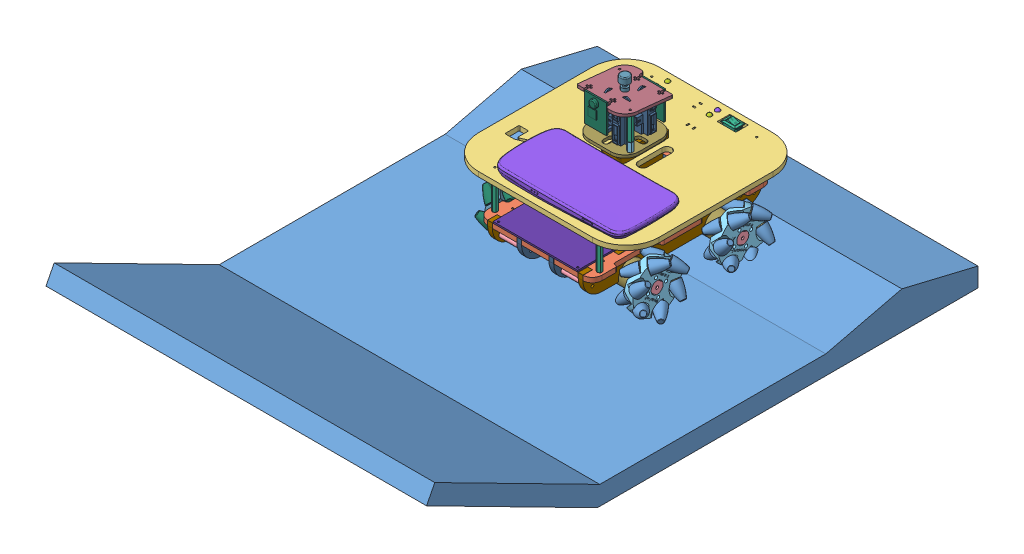
SolidWorks assembly Robo_02, configuration Valor predeterminado. Lengths in mm.
Overall size (190 176.15 190).
196 component instances, 38 part files, 87 mates.
Components (placement in the parent):
- Rampa-1: Rampa [Valor predeterminado] at (-210.2935 -119.2704 146.4332) x (0 0 -1) z (1 0 0) size (579.56 108.37 400) (hidden)
- Plataforma_1-1: Plataforma_1 [Valor predeterminado] at (-69.9818 -54.6704 16.9892) size (120 5 190)
- Plataforma_2-1: Plataforma_2 [Valor predeterminado] at (-109.9818 -15.1704 16.9892) size (190 5 190)
- PC-Standoff - 25mm - FF-1: PC-Standoff - 25mm - FF [Valor predeterminado] at (35.0182 -64.6704 1.9892) x (0 0.998329 -0.057794) z (0 0.057794 0.998329) size (6.5 25 6.5)
- PC-Standoff - 25mm - FF-2: PC-Standoff - 25mm - FF [Valor predeterminado] at (-55.1818 -64.6704 1.9892) x (0 -0.434626 0.900611) z (0 0.900611 0.434626) size (6.5 25 6.5)
- PC-Standoff - 25mm - FF-3: PC-Standoff - 25mm - FF [Valor predeterminado] at (-55.1818 -64.6704 -168.0108) x (0 -0.434626 0.900611) z (0 0.900611 0.434626) size (6.5 25 6.5)
- PC-Standoff - 25mm - FF-4: PC-Standoff - 25mm - FF [Valor predeterminado] at (35.0182 -64.6704 -168.0108) x (0 0.998329 -0.057794) z (0 0.057794 0.998329) size (6.5 25 6.5)
- PC-Standoff - 9.5mm - FF-1: PC-Standoff - 9.5mm - FF [Valor predeterminado] at (-64.9818 -24.6704 -0.5108) x (0.618827 0 0.785527) z (-0.785527 0 0.618827) size (5.5 9.5 4.76)
- PC-Standoff - 9.5mm - FF-2: PC-Standoff - 9.5mm - FF [Valor predeterminado] at (45.0182 -24.6704 -0.5108) x (0 0 1) z (-1 0 0) size (5.5 9.5 4.76)
- PC-Standoff - 9.5mm - FF-3: PC-Standoff - 9.5mm - FF [Valor predeterminado] at (-64.9818 -24.6704 -165.5108) x (0 0 1) z (-1 0 0) size (5.5 9.5 4.76)
- PC-Standoff - 9.5mm - FF-4: PC-Standoff - 9.5mm - FF [Valor predeterminado] at (45.0182 -24.6704 -165.5108) x (0.176181 0 0.984358) z (-0.984358 0 0.176181) size (5.5 9.5 4.76)
- PC-Standoff - 25mm-6: PC-Standoff - 25mm [Valor predeterminado] at (45.0182 -24.6704 -165.5108) x (-0.176181 0 -0.984358) z (-0.984358 0 0.176181) size (5.5 29.76 4.76)
- PC-Standoff - 25mm-7: PC-Standoff - 25mm [Valor predeterminado] at (45.0182 -24.6704 -0.5108) x (0 0 -1) z (-1 0 0) size (5.5 29.76 4.76)
- PC-Standoff - 25mm-8: PC-Standoff - 25mm [Valor predeterminado] at (-64.9818 -24.6704 -0.5108) x (0 0 -1) z (-1 0 0) size (5.5 29.76 4.76)
- PC-Standoff - 25mm-1: PC-Standoff - 25mm [Valor predeterminado] at (-64.9818 -24.6704 -165.5108) x (0 0 -1) z (-1 0 0) size (5.5 29.76 4.76)
- bateriaLiPO-2: bateriaLiPO [Valor predeterminado] at (-61.3132 -20.1704 -106.4354) x (0 0 1) z (0 -1 0) size (105 34 24)
- Nexus-1: Nexus [Default] at (-25.3253 -39.7124 4.2312) x (0.005944 0 0.999982) z (0 1 0) size (78.79 147.01 23.11)
- viga_motor_1-1: viga_motor_1 [Valor predeterminado] at (35.0182 -74.6704 11.9892) x (0 0 -1) z (1 0 0) size (190 25 5)
- viga_motor_2-1: viga_motor_2 [Valor predeterminado] at (4.3182 -74.6704 11.9892) x (0 0 -1) z (1 0 0) size (190 25 5)
- viga_motor_2-3: viga_motor_2 [Valor predeterminado] at (-29.4818 -74.6704 11.9892) x (0 0 -1) z (1 0 0) size (190 25 5)
- viga_motor_1-2: viga_motor_1 [Valor predeterminado] at (-60.1818 -74.6704 11.9892) x (0 0 -1) z (1 0 0) size (190 25 5)
- Motor-7: Motor [Valor predeterminado] at (-22.1818 -72.6522 -31.5439) x (0 -0.006022 0.999982) z (-1 0 0) size (25 25 76.2)
  - Motor-1: Motor [Valor predeterminado] at (-6.4714 0.7429 0) size (24.4 24.4 45.8)
  - Motor_Redutor-1: Motor_Redutor [Valor predeterminado] at (-6.4714 0.7429 30.8) size (25 25 33.5)
  - Encoder-1: Encoder [Valor predeterminado] at (-6.4714 0.7429 -2) x (1 0 0) z (0 1 0) size (23 9.9 23)
- Motor-8: Motor [Valor predeterminado] at (-22.1818 -70.3376 -134.3418) x (0 0.122928 -0.992416) z (-1 0 0) size (25 25 76.2)
  - Motor-1: Motor [Valor predeterminado] at (-6.4714 0.7429 0) size (24.4 24.4 45.8)
  - Motor_Redutor-1: Motor_Redutor [Valor predeterminado] at (-6.4714 0.7429 30.8) size (25 25 33.5)
  - Encoder-1: Encoder [Valor predeterminado] at (-6.4714 0.7429 -2) x (1 0 0) z (0 1 0) size (23 9.9 23)
- Motor-1: Motor [Valor predeterminado] at (2.2182 -71.179 -121.5336) x (0 -0.007948 0.999968) z (1 0 0) size (25 25 76.2)
  - Motor-1: Motor [Valor predeterminado] at (-6.4714 0.7429 0) size (24.4 24.4 45.8)
  - Motor_Redutor-1: Motor_Redutor [Valor predeterminado] at (-6.4714 0.7429 30.8) size (25 25 33.5)
  - Encoder-1: Encoder [Valor predeterminado] at (-6.4714 0.7429 -2) x (1 0 0) z (0 1 0) size (23 9.9 23)
- Motor-2: Motor [Valor predeterminado] at (2.2182 -73.8625 -31.8089) x (0 -0.412409 0.910999) z (1 0 0) size (25 25 76.2)
  - Motor-1: Motor [Valor predeterminado] at (-6.4714 0.7429 0) size (24.4 24.4 45.8)
  - Motor_Redutor-1: Motor_Redutor [Valor predeterminado] at (-6.4714 0.7429 30.8) size (25 25 33.5)
  - Encoder-1: Encoder [Valor predeterminado] at (-6.4714 0.7429 -2) x (1 0 0) z (0 1 0) size (23 9.9 23)
- Mecanum Wheel B-3: Mecanum Wheel B [Valor predeterminado] at (-98.1018 -64.626 -40.1882) x (-1 0 0) z (0 -0.940085 0.340939) size (40.55 59.83 66.05)
  - Mecanum Hub Mirrored B R2-1: Mecanum Hub Mirrored B R2 [Valor predeterminado] at (-14.8574 0.4229 7.5528) size (9.53 50.8 50.8)
  - rubber roller_1-1: rubber roller_1 [Valor predeterminado] at (-17.3237 21.0604 5.0865) x (-0.707107 0 -0.707107) z (0.499904 -0.707242 -0.499904) size (15.88 13.22 13.13)
  - rubber roller_1-2: rubber roller_1 [Valor predeterminado] at (-17.3231 12.877 24.1925) x (-0.707107 0.612372 -0.353553) z (0.253872 -0.246803 -0.93522) size (15.88 13.22 13.13)
  - rubber roller_1-3: rubber roller_1 [Valor predeterminado] at (-17.3231 -7.7605 26.6582) x (-0.707107 0.612372 0.353553) z (-0.391226 -0.75531 0.525784) size (15.88 13.22 13.13)
  - rubber roller_1-4: rubber roller_1 [Valor predeterminado] at (-17.3231 -20.2146 10.0185) x (-0.707107 0 0.707107) z (0.562502 0.605957 0.562502) size (15.88 13.22 13.13)
  - rubber roller_1-5: rubber roller_1 [Valor predeterminado] at (-17.3231 8.6063 -11.5527) x (-0.707107 -0.612372 -0.353553) z (-0.707107 0.61243 0.353453) size (15.88 13.22 13.13)
  - rubber roller_1-6: rubber roller_1 [Valor predeterminado] at (-17.3231 -12.0312 -9.087) x (-0.707107 -0.612372 0.353553) z (-0.5772 0.788695 0.211661) size (15.88 13.22 13.13)
  - rubber roller_1-7: rubber roller_1 [Valor predeterminado] at (-12.3912 -12.0317 24.1922) x (0.707107 -0.612372 -0.353553) z (-0.685872 -0.715596 -0.132296) size (15.88 13.22 13.13)
  - rubber roller_1-8: rubber roller_1 [Valor predeterminado] at (-12.3912 -20.2146 5.0865) x (0.707107 0 -0.707107) z (-0.253824 0.933352 -0.253824) size (15.88 13.22 13.13)
  - rubber roller_1-9: rubber roller_1 [Valor predeterminado] at (-12.3912 -7.76 -11.553) x (0.707107 0.612372 -0.353553) z (-0.001796 -0.498443 -0.866921) size (15.88 13.22 13.13)
  - rubber roller_1-10: rubber roller_1 [Valor predeterminado] at (-12.3912 8.6058 26.6585) x (0.707107 -0.612372 0.353553) z (0.069934 0.558113 0.826813) size (15.88 13.22 13.13)
  - rubber roller_1-11: rubber roller_1 [Valor predeterminado] at (-12.3912 12.8775 -9.0867) x (0.707107 0.612372 0.353553) z (-0.460574 0.01948 0.887408) size (15.88 13.22 13.13)
  - rubber roller_1-12: rubber roller_1 [Valor predeterminado] at (-12.3912 21.0604 10.019) x (0.707107 0 0.707107) z (-0.138038 -0.98076 0.138038) size (15.88 13.22 13.13)
  - steel pin_1-1: steel pin_1 [Valor predeterminado] at (-5.6406 21.0604 16.7696) x (-0.707107 0 -0.707107) z (-0.548656 0.630836 0.548656) size (32.38 3.18 3.18)
  - steel pin_1-2: steel pin_1 [Valor predeterminado] at (-3.4109 0.8287 31.1486) x (-0.707107 0.612372 -0.353553) z (-0.30884 -0.717251 -0.624635) size (32.38 3.18 3.18)
  - steel pin_1-3: steel pin_1 [Valor predeterminado] at (-3.4109 -19.8088 19.7021) x (-0.707107 0.612372 0.353553) z (0.672023 0.737529 0.066609) size (32.38 3.18 3.18)
  - steel pin_1-4: steel pin_1 [Valor predeterminado] at (-3.4109 -20.2146 -3.8938) x (-0.707107 0 0.707107) z (-0.643237 0.415323 -0.643237) size (32.38 3.18 3.18)
  - steel pin_1-5: steel pin_1 [Valor predeterminado] at (-3.4109 0.0171 -16.0431) x (-0.707107 -0.612372 0.353553) z (0.683232 -0.462866 0.564756) size (32.38 3.18 3.18)
  - steel pin_1-6: steel pin_1 [Valor predeterminado] at (-3.4109 20.6546 -4.5966) x (-0.707107 -0.612372 -0.353553) z (-0.635525 0.769593 -0.061923) size (32.38 3.18 3.18)
  - Flat Washer Type A Narrow_AI_FW 0.125_1-1: Flat Washer Type A Narrow_AI_FW 0.125_1 [Valor predeterminado] at (-12.9659 21.0604 9.4443) x (-0.707107 0 -0.707107) z (0.699565 0.145662 -0.699565) size (0.81 7.92 7.92)
  - Flat Washer Type A Narrow_AI_FW 0.125_1-2: Flat Washer Type A Narrow_AI_FW 0.125_1 [Valor predeterminado] at (-12.9659 12.3797 -9.3741) x (-0.707107 -0.612372 -0.353553) z (0.353553 -0.739199 0.573223) size (0.81 7.92 7.92)
  - Flat Washer Type A Narrow_AI_FW 0.125_1-3: Flat Washer Type A Narrow_AI_FW 0.125_1 [Valor predeterminado] at (-12.9659 -8.2578 -11.2656) x (-0.707107 -0.612372 0.353553) z (-0.353553 0.739199 0.573223) size (0.81 7.92 7.92)
  - Flat Washer Type A Narrow_AI_FW 0.125_1-4: Flat Washer Type A Narrow_AI_FW 0.125_1 [Valor predeterminado] at (-12.9659 -20.2146 5.6612) x (-0.707107 0 0.707107) z (-0.707107 0 -0.707107) size (0.81 7.92 7.92)
  - Flat Washer Type A Narrow_AI_FW 0.125_1-5: Flat Washer Type A Narrow_AI_FW 0.125_1 [Valor predeterminado] at (-12.9659 -11.5339 24.4796) x (-0.707107 0.612372 0.353553) z (-0.353553 -0.739199 0.573223) size (0.81 7.92 7.92)
  - Flat Washer Type A Narrow_AI_FW 0.125_1-6: Flat Washer Type A Narrow_AI_FW 0.125_1 [Valor predeterminado] at (-12.9659 9.1036 26.3711) x (-0.707107 0.612372 -0.353553) z (0.353553 0.739199 0.573223) size (0.81 7.92 7.92)
  - Flat Washer Type A Narrow_AI_FW 0.125_1-7: Flat Washer Type A Narrow_AI_FW 0.125_1 [Valor predeterminado] at (-16.7489 9.1036 -11.2656) x (0.707107 0.612372 0.353553) z (-0.353553 -0.126826 0.926777) size (0.81 7.92 7.92)
  - Flat Washer Type A Narrow_AI_FW 0.125_1-8: Flat Washer Type A Narrow_AI_FW 0.125_1 [Valor predeterminado] at (-16.7489 21.0604 5.6612) x (0.707107 0 0.707107) z (-0.707107 0 0.707107) size (0.81 7.92 7.92)
  - Flat Washer Type A Narrow_AI_FW 0.125_1-9: Flat Washer Type A Narrow_AI_FW 0.125_1 [Valor predeterminado] at (-16.7489 12.3797 24.4796) x (0.707107 -0.612372 0.353553) z (-0.353553 0.126826 0.926777) size (0.81 7.92 7.92)
  - Flat Washer Type A Narrow_AI_FW 0.125_1-10: Flat Washer Type A Narrow_AI_FW 0.125_1 [Valor predeterminado] at (-16.7489 -11.5339 -9.3741) x (0.707107 0.612372 -0.353553) z (0.353553 0.126826 0.926777) size (0.81 7.92 7.92)
  - Flat Washer Type A Narrow_AI_FW 0.125_1-11: Flat Washer Type A Narrow_AI_FW 0.125_1 [Valor predeterminado] at (-16.7489 -20.2146 9.4443) x (0.707107 0 -0.707107) z (0.707107 0 0.707107) size (0.81 7.92 7.92)
  - Flat Washer Type A Narrow_AI_FW 0.125_1-12: Flat Washer Type A Narrow_AI_FW 0.125_1 [Valor predeterminado] at (-16.7489 -8.2578 26.3711) x (0.707107 -0.612372 -0.353553) z (0.353553 -0.126826 0.926777) size (0.81 7.92 7.92)
  - Mecanum mount R2_1-1: Mecanum mount R2_1 [Valor predeterminado] at (-16.4449 0.4229 7.5528) x (-1 0 0) z (0 0 -1) size (9.53 25.4 25.4)
- Mecanum Wheel B-4: Mecanum Wheel B [Valor predeterminado] at (-98.1018 -76.851 -122.3172) x (-1 0 0) z (0 0.615302 -0.788291) size (40.55 59.83 66.05)
  - Mecanum Hub Mirrored B R2-1: Mecanum Hub Mirrored B R2 [Valor predeterminado] at (-14.8574 0.4229 7.5528) size (9.53 50.8 50.8)
  - rubber roller_1-1: rubber roller_1 [Valor predeterminado] at (-17.3237 21.0604 5.0865) x (-0.707107 0 -0.707107) z (0.499904 -0.707242 -0.499904) size (15.88 13.22 13.13)
  - rubber roller_1-2: rubber roller_1 [Valor predeterminado] at (-17.3231 12.877 24.1925) x (-0.707107 0.612372 -0.353553) z (0.253872 -0.246803 -0.93522) size (15.88 13.22 13.13)
  - rubber roller_1-3: rubber roller_1 [Valor predeterminado] at (-17.3231 -7.7605 26.6582) x (-0.707107 0.612372 0.353553) z (-0.391226 -0.75531 0.525784) size (15.88 13.22 13.13)
  - rubber roller_1-4: rubber roller_1 [Valor predeterminado] at (-17.3231 -20.2146 10.0185) x (-0.707107 0 0.707107) z (0.562502 0.605957 0.562502) size (15.88 13.22 13.13)
  - rubber roller_1-5: rubber roller_1 [Valor predeterminado] at (-17.3231 8.6063 -11.5527) x (-0.707107 -0.612372 -0.353553) z (-0.707107 0.61243 0.353453) size (15.88 13.22 13.13)
  - rubber roller_1-6: rubber roller_1 [Valor predeterminado] at (-17.3231 -12.0312 -9.087) x (-0.707107 -0.612372 0.353553) z (-0.5772 0.788695 0.211661) size (15.88 13.22 13.13)
  - rubber roller_1-7: rubber roller_1 [Valor predeterminado] at (-12.3912 -12.0317 24.1922) x (0.707107 -0.612372 -0.353553) z (-0.685872 -0.715596 -0.132296) size (15.88 13.22 13.13)
  - rubber roller_1-8: rubber roller_1 [Valor predeterminado] at (-12.3912 -20.2146 5.0865) x (0.707107 0 -0.707107) z (-0.253824 0.933352 -0.253824) size (15.88 13.22 13.13)
  - rubber roller_1-9: rubber roller_1 [Valor predeterminado] at (-12.3912 -7.76 -11.553) x (0.707107 0.612372 -0.353553) z (-0.001796 -0.498443 -0.866921) size (15.88 13.22 13.13)
  - rubber roller_1-10: rubber roller_1 [Valor predeterminado] at (-12.3912 8.6058 26.6585) x (0.707107 -0.612372 0.353553) z (0.069934 0.558113 0.826813) size (15.88 13.22 13.13)
  - rubber roller_1-11: rubber roller_1 [Valor predeterminado] at (-12.3912 12.8775 -9.0867) x (0.707107 0.612372 0.353553) z (-0.460574 0.01948 0.887408) size (15.88 13.22 13.13)
  - rubber roller_1-12: rubber roller_1 [Valor predeterminado] at (-12.3912 21.0604 10.019) x (0.707107 0 0.707107) z (-0.138038 -0.98076 0.138038) size (15.88 13.22 13.13)
  - steel pin_1-1: steel pin_1 [Valor predeterminado] at (-5.6406 21.0604 16.7696) x (-0.707107 0 -0.707107) z (-0.548656 0.630836 0.548656) size (32.38 3.18 3.18)
  - steel pin_1-2: steel pin_1 [Valor predeterminado] at (-3.4109 0.8287 31.1486) x (-0.707107 0.612372 -0.353553) z (-0.30884 -0.717251 -0.624635) size (32.38 3.18 3.18)
  - steel pin_1-3: steel pin_1 [Valor predeterminado] at (-3.4109 -19.8088 19.7021) x (-0.707107 0.612372 0.353553) z (0.672023 0.737529 0.066609) size (32.38 3.18 3.18)
  - steel pin_1-4: steel pin_1 [Valor predeterminado] at (-3.4109 -20.2146 -3.8938) x (-0.707107 0 0.707107) z (-0.643237 0.415323 -0.643237) size (32.38 3.18 3.18)
  - steel pin_1-5: steel pin_1 [Valor predeterminado] at (-3.4109 0.0171 -16.0431) x (-0.707107 -0.612372 0.353553) z (0.683232 -0.462866 0.564756) size (32.38 3.18 3.18)
  - steel pin_1-6: steel pin_1 [Valor predeterminado] at (-3.4109 20.6546 -4.5966) x (-0.707107 -0.612372 -0.353553) z (-0.635525 0.769593 -0.061923) size (32.38 3.18 3.18)
  - Flat Washer Type A Narrow_AI_FW 0.125_1-1: Flat Washer Type A Narrow_AI_FW 0.125_1 [Valor predeterminado] at (-12.9659 21.0604 9.4443) x (-0.707107 0 -0.707107) z (0.699565 0.145662 -0.699565) size (0.81 7.92 7.92)
  - Flat Washer Type A Narrow_AI_FW 0.125_1-2: Flat Washer Type A Narrow_AI_FW 0.125_1 [Valor predeterminado] at (-12.9659 12.3797 -9.3741) x (-0.707107 -0.612372 -0.353553) z (0.353553 -0.739199 0.573223) size (0.81 7.92 7.92)
  - Flat Washer Type A Narrow_AI_FW 0.125_1-3: Flat Washer Type A Narrow_AI_FW 0.125_1 [Valor predeterminado] at (-12.9659 -8.2578 -11.2656) x (-0.707107 -0.612372 0.353553) z (-0.353553 0.739199 0.573223) size (0.81 7.92 7.92)
  - Flat Washer Type A Narrow_AI_FW 0.125_1-4: Flat Washer Type A Narrow_AI_FW 0.125_1 [Valor predeterminado] at (-12.9659 -20.2146 5.6612) x (-0.707107 0 0.707107) z (-0.707107 0 -0.707107) size (0.81 7.92 7.92)
  - Flat Washer Type A Narrow_AI_FW 0.125_1-5: Flat Washer Type A Narrow_AI_FW 0.125_1 [Valor predeterminado] at (-12.9659 -11.5339 24.4796) x (-0.707107 0.612372 0.353553) z (-0.353553 -0.739199 0.573223) size (0.81 7.92 7.92)
  - Flat Washer Type A Narrow_AI_FW 0.125_1-6: Flat Washer Type A Narrow_AI_FW 0.125_1 [Valor predeterminado] at (-12.9659 9.1036 26.3711) x (-0.707107 0.612372 -0.353553) z (0.353553 0.739199 0.573223) size (0.81 7.92 7.92)
  - Flat Washer Type A Narrow_AI_FW 0.125_1-7: Flat Washer Type A Narrow_AI_FW 0.125_1 [Valor predeterminado] at (-16.7489 9.1036 -11.2656) x (0.707107 0.612372 0.353553) z (-0.353553 -0.126826 0.926777) size (0.81 7.92 7.92)
  - Flat Washer Type A Narrow_AI_FW 0.125_1-8: Flat Washer Type A Narrow_AI_FW 0.125_1 [Valor predeterminado] at (-16.7489 21.0604 5.6612) x (0.707107 0 0.707107) z (-0.707107 0 0.707107) size (0.81 7.92 7.92)
  - Flat Washer Type A Narrow_AI_FW 0.125_1-9: Flat Washer Type A Narrow_AI_FW 0.125_1 [Valor predeterminado] at (-16.7489 12.3797 24.4796) x (0.707107 -0.612372 0.353553) z (-0.353553 0.126826 0.926777) size (0.81 7.92 7.92)
  - Flat Washer Type A Narrow_AI_FW 0.125_1-10: Flat Washer Type A Narrow_AI_FW 0.125_1 [Valor predeterminado] at (-16.7489 -11.5339 -9.3741) x (0.707107 0.612372 -0.353553) z (0.353553 0.126826 0.926777) size (0.81 7.92 7.92)
  - Flat Washer Type A Narrow_AI_FW 0.125_1-11: Flat Washer Type A Narrow_AI_FW 0.125_1 [Valor predeterminado] at (-16.7489 -20.2146 9.4443) x (0.707107 0 -0.707107) z (0.707107 0 0.707107) size (0.81 7.92 7.92)
  - Flat Washer Type A Narrow_AI_FW 0.125_1-12: Flat Washer Type A Narrow_AI_FW 0.125_1 [Valor predeterminado] at (-16.7489 -8.2578 26.3711) x (0.707107 -0.612372 -0.353553) z (0.353553 -0.126826 0.926777) size (0.81 7.92 7.92)
  - Mecanum mount R2_1-1: Mecanum mount R2_1 [Valor predeterminado] at (-16.4449 0.4229 7.5528) x (-1 0 0) z (0 0 -1) size (9.53 25.4 25.4)
- Mecanum Wheel A-1: Mecanum Wheel A [Valor predeterminado] at (38.7135 -104.9748 -174.5041) x (-1 0 0) z (0 0.406167 0.913799) size (39.77 58.4 65.62)
  - rubber roller-1: rubber roller [Valor predeterminado] at (-22.1009 9.2708 53.4652) x (0.707107 0 -0.707107) z (0.389805 0.834329 0.389805) size (15.87 12.51 12.51)
  - rubber roller-2: rubber roller [Valor predeterminado] at (-22.1014 1.0874 72.5712) x (0.707107 0.612372 -0.353553) z (0.253872 -0.686523 -0.681348) size (15.87 12.51 12.51)
  - rubber roller-3: rubber roller [Valor predeterminado] at (-22.1014 -19.5501 75.0369) x (0.707107 0.612372 0.353553) z (-0.391226 -0.077687 0.91701) size (15.87 12.51 12.51)
  - rubber roller-4: rubber roller [Valor predeterminado] at (-22.1014 -32.0042 58.3971) x (0.707107 0 0.707107) z (-0.29752 0.907173 0.29752) size (15.87 12.51 12.51)
  - rubber roller-5: rubber roller [Valor predeterminado] at (-22.1009 -3.1838 36.8257) x (0.707107 -0.612372 -0.353553) z (0.69392 0.504841 0.51343) size (15.87 12.51 12.51)
  - rubber roller-6: rubber roller [Valor predeterminado] at (-22.1014 -23.8208 39.2917) x (0.707107 -0.612372 0.353553) z (-0.5772 -0.211044 0.788861) size (15.87 12.51 12.51)
  - rubber roller-7: rubber roller [Valor predeterminado] at (-27.0334 -23.8213 72.5709) x (-0.707107 -0.612372 -0.353553) z (-0.685872 0.47237 0.553576) size (15.87 12.51 12.51)
  - rubber roller-8: rubber roller [Valor predeterminado] at (-27.0334 -32.0042 53.4652) x (-0.707107 0 -0.707107) z (0.707107 0 -0.707107) size (15.87 12.51 12.51)
  - rubber roller-9: rubber roller [Valor predeterminado] at (-27.0334 -19.5496 36.8257) x (-0.707107 0.612372 -0.353553) z (0.622049 0.300954 -0.722829) size (15.87 12.51 12.51)
  - rubber roller-10: rubber roller [Valor predeterminado] at (-27.0334 -3.1838 75.0371) x (-0.707107 -0.612372 0.353553) z (-0.548605 0.159643 -0.820699) size (15.87 12.51 12.51)
  - rubber roller-11: rubber roller [Valor predeterminado] at (-27.0328 1.0874 39.2917) x (-0.707107 0.612372 0.353553) z (0.670094 0.420673 0.611562) size (15.87 12.51 12.51)
  - rubber roller-12: rubber roller [Valor predeterminado] at (-27.0328 9.2708 58.3971) x (-0.707107 0 0.707107) z (-0.318668 -0.892693 -0.318668) size (15.87 12.51 12.51)
  - steel pin-1: steel pin [Valor predeterminado] at (-36.0131 9.2708 67.3774) x (0.707107 0 -0.707107) z (-0.417696 -0.806883 -0.417696) size (32.38 3.18 3.18)
  - steel pin-2: steel pin [Valor predeterminado] at (-36.0136 -10.9609 79.5273) x (0.707107 0.612372 -0.353553) z (0.662238 -0.748788 0.027538) size (32.38 3.18 3.18)
  - steel pin-3: steel pin [Valor predeterminado] at (-36.0136 -31.5984 68.0808) x (0.707107 0.612372 0.353553) z (0.672023 -0.426449 -0.605414) size (32.38 3.18 3.18)
  - steel pin-4: steel pin [Valor predeterminado] at (-36.0136 -32.0042 44.4849) x (0.707107 0 0.707107) z (-0.643237 0.415323 0.643237) size (32.38 3.18 3.18)
  - steel pin-5: steel pin [Valor predeterminado] at (-36.0136 -11.7725 32.3356) x (0.707107 -0.612372 0.353553) z (0.683232 0.720526 -0.118476) size (32.38 3.18 3.18)
  - steel pin-6: steel pin [Valor predeterminado] at (-36.0131 8.8646 43.7818) x (0.707107 -0.612372 -0.353553) z (-0.168488 -0.631514 0.756837) size (32.38 3.18 3.18)
  - Flat Washer Type A Narrow_AI_FW 0.125-1: Flat Washer Type A Narrow_AI_FW 0.125 [Valor predeterminado] at (-26.4586 9.2708 57.8229) x (0.707107 0 -0.707107) z (0.707107 0 0.707107) size (0.81 7.92 7.92)
  - Flat Washer Type A Narrow_AI_FW 0.125-2: Flat Washer Type A Narrow_AI_FW 0.125 [Valor predeterminado] at (-26.4586 0.5902 39.0046) x (0.707107 -0.612372 -0.353553) z (0.353553 -0.126826 0.926777) size (0.81 7.92 7.92)
  - Flat Washer Type A Narrow_AI_FW 0.125-3: Flat Washer Type A Narrow_AI_FW 0.125 [Valor predeterminado] at (-26.4586 -20.0473 37.1131) x (0.707107 -0.612372 0.353553) z (-0.353553 0.126826 0.926777) size (0.81 7.92 7.92)
  - Flat Washer Type A Narrow_AI_FW 0.125-4: Flat Washer Type A Narrow_AI_FW 0.125 [Valor predeterminado] at (-26.4586 -32.0042 54.0399) x (0.707107 0 0.707107) z (-0.707107 0 0.707107) size (0.81 7.92 7.92)
  - Flat Washer Type A Narrow_AI_FW 0.125-5: Flat Washer Type A Narrow_AI_FW 0.125 [Valor predeterminado] at (-26.4586 -23.3235 72.8583) x (0.707107 0.612372 0.353553) z (-0.353553 -0.126826 0.926777) size (0.81 7.92 7.92)
  - Flat Washer Type A Narrow_AI_FW 0.125-6: Flat Washer Type A Narrow_AI_FW 0.125 [Valor predeterminado] at (-26.4586 -2.686 74.7498) x (0.707107 0.612372 -0.353553) z (0.353553 0.126826 0.926777) size (0.81 7.92 7.92)
  - Flat Washer Type A Narrow_AI_FW 0.125-7: Flat Washer Type A Narrow_AI_FW 0.125 [Valor predeterminado] at (-22.6756 -2.686 37.1131) x (-0.707107 0.612372 0.353553) z (0.532501 0.13219 0.836043) size (0.81 7.92 7.92)
  - Flat Washer Type A Narrow_AI_FW 0.125-8: Flat Washer Type A Narrow_AI_FW 0.125 [Valor predeterminado] at (-22.6756 9.2708 54.0399) x (-0.707107 0 0.707107) z (-0.707107 0 -0.707107) size (0.81 7.92 7.92)
  - Flat Washer Type A Narrow_AI_FW 0.125-9: Flat Washer Type A Narrow_AI_FW 0.125 [Valor predeterminado] at (-22.6756 0.5902 72.8583) x (-0.707107 -0.612372 0.353553) z (-0.353553 0.739199 0.573223) size (0.81 7.92 7.92)
  - Flat Washer Type A Narrow_AI_FW 0.125-10: Flat Washer Type A Narrow_AI_FW 0.125 [Valor predeterminado] at (-22.6756 -23.3235 39.0046) x (-0.707107 0.612372 -0.353553) z (0.353553 0.739199 0.573223) size (0.81 7.92 7.92)
  - Flat Washer Type A Narrow_AI_FW 0.125-11: Flat Washer Type A Narrow_AI_FW 0.125 [Valor predeterminado] at (-22.6756 -32.0042 57.8229) x (-0.707107 0 -0.707107) z (0.707107 0 -0.707107) size (0.81 7.92 7.92)
  - Flat Washer Type A Narrow_AI_FW 0.125-12: Flat Washer Type A Narrow_AI_FW 0.125 [Valor predeterminado] at (-22.6756 -20.0473 74.7498) x (-0.707107 -0.612372 -0.353553) z (0.353553 -0.739199 0.573223) size (0.81 7.92 7.92)
  - Mecanum mount R2-1: Mecanum mount R2 [Valor predeterminado] at (-22.9796 -11.3667 55.9314) size (9.53 25.4 25.4)
  - Mecanum Hub A R2-1: Mecanum Hub A R2 [Valor predeterminado] at (-24.5671 -11.3667 55.9314) size (9.53 50.8 50.8)
- Mecanum Wheel A-3: Mecanum Wheel A [Valor predeterminado] at (38.7135 -115.3387 -74.9977) x (-1 0 0) z (0 0.617286 0.786739) size (39.77 58.4 65.62)
  - rubber roller-1: rubber roller [Valor predeterminado] at (-22.1009 9.2708 53.4652) x (0.707107 0 -0.707107) z (0.389805 0.834329 0.389805) size (15.87 12.51 12.51)
  - rubber roller-2: rubber roller [Valor predeterminado] at (-22.1014 1.0874 72.5712) x (0.707107 0.612372 -0.353553) z (0.253872 -0.686523 -0.681348) size (15.87 12.51 12.51)
  - rubber roller-3: rubber roller [Valor predeterminado] at (-22.1014 -19.5501 75.0369) x (0.707107 0.612372 0.353553) z (-0.391226 -0.077687 0.91701) size (15.87 12.51 12.51)
  - rubber roller-4: rubber roller [Valor predeterminado] at (-22.1014 -32.0042 58.3971) x (0.707107 0 0.707107) z (-0.29752 0.907173 0.29752) size (15.87 12.51 12.51)
  - rubber roller-5: rubber roller [Valor predeterminado] at (-22.1009 -3.1838 36.8257) x (0.707107 -0.612372 -0.353553) z (0.69392 0.504841 0.51343) size (15.87 12.51 12.51)
  - rubber roller-6: rubber roller [Valor predeterminado] at (-22.1014 -23.8208 39.2917) x (0.707107 -0.612372 0.353553) z (-0.5772 -0.211044 0.788861) size (15.87 12.51 12.51)
  - rubber roller-7: rubber roller [Valor predeterminado] at (-27.0334 -23.8213 72.5709) x (-0.707107 -0.612372 -0.353553) z (-0.685872 0.47237 0.553576) size (15.87 12.51 12.51)
  - rubber roller-8: rubber roller [Valor predeterminado] at (-27.0334 -32.0042 53.4652) x (-0.707107 0 -0.707107) z (0.707107 0 -0.707107) size (15.87 12.51 12.51)
  - rubber roller-9: rubber roller [Valor predeterminado] at (-27.0334 -19.5496 36.8257) x (-0.707107 0.612372 -0.353553) z (0.622049 0.300954 -0.722829) size (15.87 12.51 12.51)
  - rubber roller-10: rubber roller [Valor predeterminado] at (-27.0334 -3.1838 75.0371) x (-0.707107 -0.612372 0.353553) z (-0.548605 0.159643 -0.820699) size (15.87 12.51 12.51)
  - rubber roller-11: rubber roller [Valor predeterminado] at (-27.0328 1.0874 39.2917) x (-0.707107 0.612372 0.353553) z (0.670094 0.420673 0.611562) size (15.87 12.51 12.51)
  - rubber roller-12: rubber roller [Valor predeterminado] at (-27.0328 9.2708 58.3971) x (-0.707107 0 0.707107) z (-0.318668 -0.892693 -0.318668) size (15.87 12.51 12.51)
  - steel pin-1: steel pin [Valor predeterminado] at (-36.0131 9.2708 67.3774) x (0.707107 0 -0.707107) z (-0.417696 -0.806883 -0.417696) size (32.38 3.18 3.18)
  - steel pin-2: steel pin [Valor predeterminado] at (-36.0136 -10.9609 79.5273) x (0.707107 0.612372 -0.353553) z (0.662238 -0.748788 0.027538) size (32.38 3.18 3.18)
  - steel pin-3: steel pin [Valor predeterminado] at (-36.0136 -31.5984 68.0808) x (0.707107 0.612372 0.353553) z (0.672023 -0.426449 -0.605414) size (32.38 3.18 3.18)
  - steel pin-4: steel pin [Valor predeterminado] at (-36.0136 -32.0042 44.4849) x (0.707107 0 0.707107) z (-0.643237 0.415323 0.643237) size (32.38 3.18 3.18)
  - steel pin-5: steel pin [Valor predeterminado] at (-36.0136 -11.7725 32.3356) x (0.707107 -0.612372 0.353553) z (0.683232 0.720526 -0.118476) size (32.38 3.18 3.18)
  - steel pin-6: steel pin [Valor predeterminado] at (-36.0131 8.8646 43.7818) x (0.707107 -0.612372 -0.353553) z (-0.168488 -0.631514 0.756837) size (32.38 3.18 3.18)
  - Flat Washer Type A Narrow_AI_FW 0.125-1: Flat Washer Type A Narrow_AI_FW 0.125 [Valor predeterminado] at (-26.4586 9.2708 57.8229) x (0.707107 0 -0.707107) z (0.707107 0 0.707107) size (0.81 7.92 7.92)
  - Flat Washer Type A Narrow_AI_FW 0.125-2: Flat Washer Type A Narrow_AI_FW 0.125 [Valor predeterminado] at (-26.4586 0.5902 39.0046) x (0.707107 -0.612372 -0.353553) z (0.353553 -0.126826 0.926777) size (0.81 7.92 7.92)
  - Flat Washer Type A Narrow_AI_FW 0.125-3: Flat Washer Type A Narrow_AI_FW 0.125 [Valor predeterminado] at (-26.4586 -20.0473 37.1131) x (0.707107 -0.612372 0.353553) z (-0.353553 0.126826 0.926777) size (0.81 7.92 7.92)
  - Flat Washer Type A Narrow_AI_FW 0.125-4: Flat Washer Type A Narrow_AI_FW 0.125 [Valor predeterminado] at (-26.4586 -32.0042 54.0399) x (0.707107 0 0.707107) z (-0.707107 0 0.707107) size (0.81 7.92 7.92)
  - Flat Washer Type A Narrow_AI_FW 0.125-5: Flat Washer Type A Narrow_AI_FW 0.125 [Valor predeterminado] at (-26.4586 -23.3235 72.8583) x (0.707107 0.612372 0.353553) z (-0.353553 -0.126826 0.926777) size (0.81 7.92 7.92)
  - Flat Washer Type A Narrow_AI_FW 0.125-6: Flat Washer Type A Narrow_AI_FW 0.125 [Valor predeterminado] at (-26.4586 -2.686 74.7498) x (0.707107 0.612372 -0.353553) z (0.353553 0.126826 0.926777) size (0.81 7.92 7.92)
  - Flat Washer Type A Narrow_AI_FW 0.125-7: Flat Washer Type A Narrow_AI_FW 0.125 [Valor predeterminado] at (-22.6756 -2.686 37.1131) x (-0.707107 0.612372 0.353553) z (0.532501 0.13219 0.836043) size (0.81 7.92 7.92)
  - Flat Washer Type A Narrow_AI_FW 0.125-8: Flat Washer Type A Narrow_AI_FW 0.125 [Valor predeterminado] at (-22.6756 9.2708 54.0399) x (-0.707107 0 0.707107) z (-0.707107 0 -0.707107) size (0.81 7.92 7.92)
  - Flat Washer Type A Narrow_AI_FW 0.125-9: Flat Washer Type A Narrow_AI_FW 0.125 [Valor predeterminado] at (-22.6756 0.5902 72.8583) x (-0.707107 -0.612372 0.353553) z (-0.353553 0.739199 0.573223) size (0.81 7.92 7.92)
  - Flat Washer Type A Narrow_AI_FW 0.125-10: Flat Washer Type A Narrow_AI_FW 0.125 [Valor predeterminado] at (-22.6756 -23.3235 39.0046) x (-0.707107 0.612372 -0.353553) z (0.353553 0.739199 0.573223) size (0.81 7.92 7.92)
  - Flat Washer Type A Narrow_AI_FW 0.125-11: Flat Washer Type A Narrow_AI_FW 0.125 [Valor predeterminado] at (-22.6756 -32.0042 57.8229) x (-0.707107 0 -0.707107) z (0.707107 0 -0.707107) size (0.81 7.92 7.92)
  - Flat Washer Type A Narrow_AI_FW 0.125-12: Flat Washer Type A Narrow_AI_FW 0.125 [Valor predeterminado] at (-22.6756 -20.0473 74.7498) x (-0.707107 -0.612372 -0.353553) z (0.353553 -0.739199 0.573223) size (0.81 7.92 7.92)
  - Mecanum mount R2-1: Mecanum mount R2 [Valor predeterminado] at (-22.9796 -11.3667 55.9314) size (9.53 25.4 25.4)
  - Mecanum Hub A R2-1: Mecanum Hub A R2 [Valor predeterminado] at (-24.5671 -11.3667 55.9314) size (9.53 50.8 50.8)
- Switch_KCD11-1: Switch_KCD11 [KCD11-A-101-O11XX] at (19.9682 -18.8704 -165.6608) size (15.06 19.01 10.5)
- LED_green-1: LED_green [Default] at (-52.1994 -15.1704 -169.3256) x (0.994234 0 0.107236) z (-0.107236 0 0.994234) size (5.6 12.7 5.6)
- LED_red-1: LED_red [Default] at (0.2682 -15.1704 -169.3256) x (0.999922 0 0.012514) z (-0.012514 0 0.999922) size (5.6 12.7 5.6)
- LED_green-2: LED_green [Default] at (0.2682 -15.1704 -160.8008) x (0.994234 0 0.107236) z (-0.107236 0 0.994234) size (5.6 12.7 5.6)
- Sensores-1: Sensores [Valor predeterminado] at (-10.2028 -17.7534 -89.9373) x (0 0 -1) z (1 0 0) size (63.71 96.45 60)
  - Servo-HS-311-1: Servo-HS-311 [Default] at (-16.8266 -17.817 9.779) size (52.83 41.27 19.56)
  - Sharp_ir_sensor-1: Sharp_ir_sensor [Default] at (-0.6056 58.92 -3.1195) x (0 -1 0) z (1 0 0) size (44.7 18.85 13.49)
  - Servo_horn-1: Servo_horn [Valor predeterminado] at (-7.5556 20.029 0) x (-1 0 0) z (0 0 -1) size (10 6.5 10)
  - Base_sensores_1-2: Base_sensores_1 [Valor predeterminado] at (-7.5556 24.329 0) size (53 3 53)
  - Sharp_ir_sensor-3: Sharp_ir_sensor [Default] at (-10.6751 58.92 -6.95) x (0 -1 0) z (0 0 -1) size (44.7 18.85 13.49)
  - Sharp_ir_sensor-4: Sharp_ir_sensor [Default] at (-14.5056 58.92 3.1195) x (0 -1 0) z (-1 0 0) size (44.7 18.85 13.49)
  - Sharp_ir_sensor-5: Sharp_ir_sensor [Default] at (-4.4361 58.92 6.95) x (0 -1 0) z (0 0 1) size (44.7 18.85 13.49)
  - PC-Standoff - 9.5mm - FF-1: PC-Standoff - 9.5mm - FF [Valor predeterminado] at (-23.2982 27.329 21.3995) x (-1 0 -0.000559) z (0.000559 0 -1) size (5.5 9.5 4.76)
  - PC-Standoff - 25mm-1: PC-Standoff - 25mm [Valor predeterminado] at (-23.2982 36.829 21.3995) size (5.5 29.76 4.76)
  - PC-Standoff - 9.5mm - FF-2: PC-Standoff - 9.5mm - FF [Valor predeterminado] at (8.1871 27.329 -21.3995) x (0.159853 0 0.987141) z (-0.987141 0 0.159853) size (5.5 9.5 4.76)
  - PC-Standoff - 25mm-2: PC-Standoff - 25mm [Valor predeterminado] at (8.1871 36.829 -21.3995) x (0.93482 0 0.355121) z (-0.355121 0 0.93482) size (5.5 29.76 4.76)
  - Base_sensores_2-2: Base_sensores_2 [Valor predeterminado] at (-7.5556 61.829 0) x (-1 0 0) z (0 0 -1) size (53 3 60)
  - Push_button_1-1: Push_button_1 [Valor predeterminado] at (-7.5556 55.829 0) x (0.957507 0 0.288409) z (-0.288409 0 0.957507) size (10 36.8 10)
  - sensor_temperatura-1: sensor_temperatura [Valor predeterminado] at (-28.0556 34.829 2.5) x (0 1 0) z (0 0 1) size (30 4.5 23)
  - sensor_temperatura-2: sensor_temperatura [Valor predeterminado] at (12.9444 34.829 -2.5) x (0 1 0) z (0 0 -1) size (30 4.5 23)
- Suporte_bateria_1-1: Suporte_bateria_1 [Valor predeterminado] at (-62.2376 -49.6704 -150.247) size (60 44 5)
- Suporte_bateria_1-2: Suporte_bateria_1 [Valor predeterminado] at (-62.2376 -49.1704 -60.2745) size (60 44 5)
- Interface-1: Interface [Valor predeterminado] at (34.5182 -48.0104 11.9892) x (0 -1 0) z (1 0 0) size (1.66 59.5 89)
- Sensor_luz-2: Sensor_luz [Valor predeterminado] at (-23.4936 -71.573 -82.4964) x (0 0 -1) z (-1 0 0) size (48 4.7 40)
  - Sensor_luz-1: Sensor_luz [Valor predeterminado] at (-22.1579 3.0974 0) size (45 2.7 27)
  - Base_sensor_luz-1: Base_sensor_luz [Valor predeterminado] at (-26.1148 3.0974 -33.7097) x (1 0 0) z (0 -1 0) size (48 40 3)
- Motores-1: Motores [Valor predeterminado] at (-1.5828 -49.6704 -161.2596) x (0 0 1) z (-1 0 0) size (93.5 1.66 47)
Mates (geometry in assembly coordinates):
- Coincidente1: coincident anti-aligned: plane of Plataforma_1-1 through (-69.9818 -49.6704 -178.0108) normal (0 1 0); plane of PC-Standoff - 25mm-1 through (-64.9818 -49.6704 -168.259) normal (0 -1 0)
- Coincidente15: coincident anti-aligned: plane of Plataforma_1-1 through (-69.9818 -49.6704 -178.0108) normal (0 1 0); plane of PC-Standoff - 25mm-6 through (44.534 -49.6704 -168.216) normal (0 -1 0)
- Coincidente18: coincident anti-aligned: plane of Plataforma_1-1 through (-69.9818 -49.6704 -178.0108) normal (0 1 0); plane of PC-Standoff - 25mm-7 through (45.0182 -49.6704 -3.259) normal (0 -1 0)
- Coincidente21: coincident anti-aligned: plane of Plataforma_1-1 through (-69.9818 -49.6704 -178.0108) normal (0 1 0); plane of PC-Standoff - 25mm-8 through (-64.9818 -49.6704 -3.259) normal (0 -1 0)
- Concêntrico17: concentric anti-aligned: cylinder of PC-Standoff - 25mm-8 through (-64.9818 -44.9104 -0.5108) axis (0 -1 0) radius 1.0922; cylinder of Plataforma_1-1 through (-64.9818 -54.6704 -0.5108) axis (0 1 0) radius 1
- Concêntrico18: concentric anti-aligned: cylinder of PC-Standoff - 25mm-1 through (-64.9818 -44.9104 -165.5108) axis (0 -1 0) radius 1.0922; cylinder of Plataforma_1-1 through (-64.9818 -54.6704 -165.5108) axis (0 1 0) radius 1
- Concêntrico19: concentric anti-aligned: cylinder of PC-Standoff - 25mm-6 through (45.0182 -44.9104 -165.5108) axis (0 -1 0) radius 1.0922; cylinder of Plataforma_1-1 through (45.0182 -54.6704 -165.5108) axis (0 1 0) radius 1
- Concêntrico20: concentric anti-aligned: cylinder of PC-Standoff - 25mm-7 through (45.0182 -44.9104 -0.5108) axis (0 -1 0) radius 1.0922; cylinder of Plataforma_1-1 through (45.0182 -54.6704 -0.5108) axis (0 1 0) radius 1
- Distância2: distance = 6 mm aligned: plane of Motor-1/Motor_Redutor-1 through (56.0182 -71.8704 -128.0108) normal (1 0 0); plane of Plataforma_1-1 through (50.0182 -49.6704 11.9892) normal (1 0 0)
- Coincidente42: coincident aligned: plane of Plataforma_1-1 through (-69.9818 -49.6704 -178.0108) normal (0 1 0); plane of viga_motor_1-1 through (40.0182 -49.6704 11.9892) normal (0 1 0)
- Coincidente43: coincident aligned: plane of Plataforma_1-1 through (-69.9818 -49.6704 11.9892) normal (0 0 1); plane of viga_motor_1-1 through (40.0182 -54.6704 11.9892) normal (0 0 1)
- Concêntrico26: concentric anti-aligned: cylinder of viga_motor_1-1 through (30.0182 -71.8704 -128.0108) axis (1 0 0) radius 12.5; cylinder of Motor-1/Motor_Redutor-1 through (56.0182 -71.8704 -128.0108) axis (-1 0 0) radius 12.5
- Distância4: distance = 6 mm aligned: plane of Motor-2/Motor_Redutor-1 through (56.0182 -71.8704 -38.0108) normal (1 0 0); plane of Plataforma_1-1 through (50.0182 -49.6704 11.9892) normal (1 0 0)
- Concêntrico27: concentric anti-aligned: cylinder of viga_motor_1-1 through (30.0182 -71.8704 -38.0108) axis (1 0 0) radius 12.5; cylinder of Motor-2/Motor_Redutor-1 through (56.0182 -71.8704 -38.0108) axis (-1 0 0) radius 12.5
- Coincidente44: coincident aligned: plane of Plataforma_1-1 through (-69.9818 -49.6704 -178.0108) normal (0 1 0); plane of viga_motor_2-1 through (9.3182 -49.6704 11.9892) normal (0 1 0)
- Coincidente45: coincident aligned: plane of Plataforma_1-1 through (-69.9818 -49.6704 11.9892) normal (0 0 1); plane of viga_motor_2-1 through (9.3182 -54.6704 11.9892) normal (0 0 1)
- Coincidente47: coincident anti-aligned: plane of Plataforma_1-1 through (35.0182 -54.6704 -25.5108) normal (1 0 0); plane of viga_motor_1-1 through (35.0182 -54.6704 -8.0108) normal (-1 0 0)
- Coincidente48: coincident anti-aligned: plane of Plataforma_1-1 through (4.3182 -54.6704 -115.5108) normal (1 0 0); plane of viga_motor_2-1 through (4.3182 -54.6704 -8.0108) normal (-1 0 0)
- Coincidente51: coincident aligned: plane of Plataforma_1-1 through (-69.9818 -49.6704 -178.0108) normal (0 1 0); plane of viga_motor_2-3 through (-24.4818 -49.6704 11.9892) normal (0 1 0)
- Coincidente52: coincident aligned: plane of Plataforma_1-1 through (-69.9818 -49.6704 11.9892) normal (0 0 1); plane of viga_motor_2-3 through (-24.4818 -54.6704 11.9892) normal (0 0 1)
- Coincidente53: coincident anti-aligned: plane of Plataforma_1-1 through (-29.4818 -54.6704 -25.5108) normal (1 0 0); plane of viga_motor_2-3 through (-29.4818 -54.6704 -8.0108) normal (-1 0 0)
- Coincidente54: coincident aligned: plane of Plataforma_1-1 through (-69.9818 -49.6704 -178.0108) normal (0 1 0); plane of viga_motor_1-2 through (-55.1818 -49.6704 11.9892) normal (0 1 0)
- Coincidente55: coincident aligned: plane of Plataforma_1-1 through (-69.9818 -49.6704 11.9892) normal (0 0 1); plane of viga_motor_1-2 through (-55.1818 -54.6704 11.9892) normal (0 0 1)
- Coincidente56: coincident anti-aligned: plane of Plataforma_1-1 through (-60.1818 -54.6704 -25.5108) normal (1 0 0); plane of viga_motor_1-2 through (-60.1818 -54.6704 -8.0108) normal (-1 0 0)
- Distância9: distance = 6 mm aligned: plane of Motor-7/Motor_Redutor-1 through (-75.9818 -71.8704 -38.0108) normal (-1 0 0); plane of Plataforma_1-1 through (-69.9818 -49.6704 11.9892) normal (-1 0 0)
- Concêntrico30: concentric aligned: cylinder of viga_motor_1-2 through (-65.1818 -71.8704 -38.0108) axis (1 0 0) radius 12.5; cylinder of Motor-7/Motor_Redutor-1 through (-75.9818 -71.8704 -38.0108) axis (1 0 0) radius 12.5
- Distância10: distance = 6 mm aligned: plane of Motor-8/Motor_Redutor-1 through (-75.9818 -71.8704 -128.0108) normal (-1 0 0); plane of Plataforma_1-1 through (-69.9818 -49.6704 11.9892) normal (-1 0 0)
- Concêntrico31: concentric aligned: cylinder of viga_motor_1-2 through (-65.1818 -71.8704 -128.0108) axis (1 0 0) radius 12.5; cylinder of Motor-8/Motor_Redutor-1 through (-75.9818 -71.8704 -128.0108) axis (1 0 0) radius 12.5
- Coincidente60: coincident: plane of Motor-7/Motor_Redutor-1 through (-78.4818 -71.8704 -38.0108) normal (-1 0 0); plane of Mecanum Wheel B-3/Mecanum mount R2_1-1 through (-78.4818 -71.8704 -38.0108) normal (1 0 0)
- Concêntrico34: concentric: cylinder of Motor-7/Motor_Redutor-1 through (-86.4818 -71.8704 -38.0108) axis (1 0 0) radius 2; cylinder of Mecanum Wheel B-3/Mecanum mount R2_1-1 through (-88.0068 -71.8704 -38.0108) axis (1 0 0) radius 1.5
- Coincidente61: coincident: plane of Motor-8/Motor_Redutor-1 through (-78.4818 -71.8704 -128.0108) normal (-1 0 0); plane of Mecanum Wheel B-4/Mecanum mount R2_1-1 through (-78.4818 -71.8704 -128.0108) normal (1 0 0)
- Concêntrico35: concentric: cylinder of Motor-8/Motor_Redutor-1 through (-86.4818 -71.8704 -128.0108) axis (1 0 0) radius 2; cylinder of Mecanum Wheel B-4/Mecanum mount R2_1-1 through (-88.0068 -71.8704 -128.0108) axis (1 0 0) radius 1.5
- Coincidente62: coincident: plane of Motor-1/Motor_Redutor-1 through (58.5182 -71.8704 -128.0108) normal (1 0 0); plane of Mecanum Wheel A-1/Mecanum mount R2-1 through (58.5182 -71.8704 -128.0108) normal (-1 0 0)
- Concêntrico36: concentric: cylinder of Motor-1/Motor_Redutor-1 through (66.5182 -71.8704 -128.0108) axis (-1 0 0) radius 2; cylinder of Mecanum Wheel A-1/Mecanum mount R2-1 through (68.0432 -71.8704 -128.0108) axis (-1 0 0) radius 1.5
- Coincidente64: coincident: plane of Motor-2/Motor_Redutor-1 through (58.5182 -71.8704 -38.0108) normal (1 0 0); plane of Mecanum Wheel A-3/Mecanum mount R2-1 through (58.5182 -71.8704 -38.0108) normal (-1 0 0)
- Concêntrico37: concentric: cylinder of Motor-2/Motor_Redutor-1 through (66.5182 -71.8704 -38.0108) axis (-1 0 0) radius 2; cylinder of Mecanum Wheel A-3/Mecanum mount R2-1 through (68.0432 -71.8704 -38.0108) axis (-1 0 0) radius 1.5
- Paralelo1: parallel aligned: plane of Plataforma_1-1 through (-69.9818 -49.6704 -178.0108) normal (0 1 0); plane of Rampa-1 through (189.7065 -99.2704 43.5015) normal (0 1 0)
- Paralelo2: parallel aligned: plane of viga_motor_1-1 through (40.0182 -54.6704 -8.0108) normal (1 0 0); plane of Rampa-1 through (189.7065 -561.2268 43.5015) normal (1 0 0)
- Distância11: distance = 2 mm: cylinder of Mecanum Wheel A-3/Mecanum Hub A R2-1 through (68.0432 -71.8704 -38.0108) axis (1 0 0) radius 25.4; plane of Rampa-1 through (189.7065 -99.2704 43.5015) normal (0 1 0)
- Coincidente67: coincident anti-aligned: plane of PC-Standoff - 9.5mm - FF-1 through (-63.2812 -15.1704 1.648) normal (0 1 0); plane of Plataforma_2-1 through (-104.9818 -15.1704 -178.0108) normal (0 -1 0)
- Concêntrico38: concentric aligned: cylinder of PC-Standoff - 9.5mm - FF-1 through (-64.9818 -19.9304 -0.5108) axis (0 1 0) radius 1.0922; cylinder of Plataforma_2-1 through (-64.9818 -15.1704 -0.5108) axis (0 1 0) radius 1
- Concêntrico42: concentric aligned: cylinder of PC-Standoff - 9.5mm - FF-3 through (-64.9818 -19.9304 -165.5108) axis (0 1 0) radius 1.0922; cylinder of Plataforma_2-1 through (-64.9818 -15.1704 -165.5108) axis (0 1 0) radius 1
- Coincidente71: coincident anti-aligned: plane of Plataforma_2-1 through (-19.9818 -15.1704 -114.1108) normal (1 0 0); plane of Sensores-1/Servo-HS-311-1 through (-19.9818 -2.2964 -73.1108) normal (-1 0 0)
- Coincidente72: coincident anti-aligned: plane of Plataforma_2-1 through (-5.9818 -15.1704 -73.1108) normal (0 0 -1); plane of Sensores-1/Servo-HS-311-1 through (-0.4238 -2.2964 -73.1108) normal (0 0 1)
- Concêntrico43: concentric anti-aligned: cylinder of PC-Standoff - 9.5mm - FF-4 through (45.0182 -19.9304 -165.5108) axis (0 1 0) radius 1.0922; cylinder of PC-Standoff - 25mm-6 through (45.0182 -19.9104 -165.5108) axis (0 -1 0) radius 1.0922
- Coincidente74: coincident anti-aligned: plane of PC-Standoff - 9.5mm - FF-4 through (45.5024 -24.6704 -162.8056) normal (0 -1 0); plane of PC-Standoff - 25mm-6 through (44.534 -24.6704 -168.216) normal (0 1 0)
- Coincidente75: coincident anti-aligned: plane of PC-Standoff - 9.5mm - FF-3 through (-64.9818 -24.6704 -162.7626) normal (0 -1 0); plane of PC-Standoff - 25mm-1 through (-64.9818 -24.6704 -168.259) normal (0 1 0)
- Concêntrico44: concentric anti-aligned: cylinder of PC-Standoff - 9.5mm - FF-3 through (-64.9818 -19.9304 -165.5108) axis (0 1 0) radius 1.0922; cylinder of PC-Standoff - 25mm-1 through (-64.9818 -19.9104 -165.5108) axis (0 -1 0) radius 1.0922
- Coincidente76: coincident anti-aligned: plane of PC-Standoff - 9.5mm - FF-2 through (45.0182 -24.6704 2.2374) normal (0 -1 0); plane of PC-Standoff - 25mm-7 through (45.0182 -24.6704 -3.259) normal (0 1 0)
- Concêntrico45: concentric anti-aligned: cylinder of PC-Standoff - 9.5mm - FF-2 through (45.0182 -19.9304 -0.5108) axis (0 1 0) radius 1.0922; cylinder of PC-Standoff - 25mm-7 through (45.0182 -19.9104 -0.5108) axis (0 -1 0) radius 1.0922
- Concêntrico46: concentric anti-aligned: cylinder of PC-Standoff - 9.5mm - FF-1 through (-64.9818 -19.9304 -0.5108) axis (0 1 0) radius 1.0922; cylinder of PC-Standoff - 25mm-8 through (-64.9818 -19.9104 -0.5108) axis (0 -1 0) radius 1.0922
- Coincidente77: coincident anti-aligned: plane of PC-Standoff - 9.5mm - FF-1 through (-63.2812 -24.6704 1.648) normal (0 -1 0); plane of PC-Standoff - 25mm-8 through (-64.9818 -24.6704 -3.259) normal (0 1 0)
- Coincidente79: coincident anti-aligned: plane of Plataforma_2-1 through (-104.9818 -10.1704 -178.0108) normal (0 1 0); plane of Switch_KCD11-1 through (12.4682 -10.1704 -160.4108) normal (0 -1 0)
- Distância12: distance = 2.2 mm anti-aligned: plane of Switch_KCD11-1 through (13.9682 -18.8704 -169.8608) normal (0 0 -1); plane of Plataforma_2-1 through (10.2682 -15.1704 -172.0608) normal (0 0 1)
- Distância13: distance = 3.8 mm anti-aligned: plane of Switch_KCD11-1 through (25.9682 -10.1704 -161.4608) normal (1 0 0); plane of Plataforma_2-1 through (29.7682 -15.1704 -158.9608) normal (-1 0 0)
- Coincidente81: coincident anti-aligned: plane of Plataforma_2-1 through (-104.9818 -10.1704 -178.0108) normal (0 1 0); plane of Sensores-1/Servo-HS-311-1 through (-19.9818 -10.1704 -66.7608) normal (0 -1 0)
- Coincident1: coincident anti-aligned: plane of Plataforma_2-1 through (-104.9818 -15.1704 -178.0108) normal (0 -1 0); plane of LED_green-1 through (-52.1994 -15.1704 -169.3256) normal (0 1 0)
- Concentric1: concentric anti-aligned: cylinder of Plataforma_2-1 through (-52.1994 -20.1704 -169.3256) axis (0 1 0) radius 2.35; cylinder of LED_green-1 through (-52.1994 -8.1704 -169.3256) axis (0 -1 0) radius 2.5
- Coincident2: coincident anti-aligned: plane of Plataforma_2-1 through (-104.9818 -15.1704 -178.0108) normal (0 -1 0); plane of LED_red-1 through (0.2682 -15.1704 -169.3256) normal (0 1 0)
- Concentric2: concentric anti-aligned: cylinder of Plataforma_2-1 through (0.2682 -20.1704 -169.3256) axis (0 1 0) radius 2.35; cylinder of LED_red-1 through (0.2682 -8.1704 -169.3256) axis (0 -1 0) radius 2.5
- Coincident3: coincident anti-aligned: plane of Plataforma_2-1 through (-104.9818 -15.1704 -178.0108) normal (0 -1 0); plane of LED_green-2 through (0.2682 -15.1704 -160.8008) normal (0 1 0)
- Concentric3: concentric anti-aligned: cylinder of LED_green-2 through (0.2682 -8.1704 -160.8008) axis (0 -1 0) radius 2.5; cylinder of Plataforma_2-1 through (0.2682 -20.1704 -160.8008) axis (0 1 0) radius 2.35
- Coincidente83: coincident anti-aligned: plane of Plataforma_1-1 through (-69.9818 -49.6704 -178.0108) normal (0 1 0); plane of Suporte_bateria_1-1 through (-67.2376 -49.6704 -145.247) normal (0 -1 0)
- Coincidente84: coincident anti-aligned: plane of Plataforma_1-1 through (-47.2376 -54.6704 -145.247) normal (1 0 0); plane of Suporte_bateria_1-1 through (-47.2376 -49.6704 -145.247) normal (-1 0 0)
- Coincidente85: coincident anti-aligned: plane of Plataforma_1-1 through (-47.2376 -54.6704 -145.247) normal (0 0 -1); plane of Suporte_bateria_1-1 through (-67.2376 -15.6704 -145.247) normal (0 0 1)
- Coincidente87: coincident anti-aligned: plane of Plataforma_1-1 through (-47.2376 -54.6704 -60.7745) normal (1 0 0); plane of Suporte_bateria_1-2 through (-47.2376 -49.1704 -55.2745) normal (-1 0 0)
- Coincidente90: coincident anti-aligned: plane of Plataforma_1-1 through (-47.2376 -54.6704 -55.2745) normal (0 0 -1); plane of Suporte_bateria_1-2 through (-67.2376 -15.1704 -55.2745) normal (0 0 1)
- Coincidente92: coincident anti-aligned: plane of Suporte_bateria_1-1 through (-59.7911 -84.617 -150.247) normal (1 0 0); plane of bateriaLiPO-2 through (-59.7911 -44.1704 -155.243) normal (-1 0 0)
- Coincidente94: coincident aligned: plane of Plataforma_2-1 through (-104.9818 -10.1704 -178.0108) normal (0 1 0); plane of Suporte_bateria_1-2 through (-47.2376 -10.1704 -55.2745) normal (0 1 0)
- Distância14: distance = 5 mm aligned: plane of bateriaLiPO-2 through (-25.7911 -20.1704 -155.243) normal (0 1 0); plane of Suporte_bateria_1-2 through (-67.2376 -15.1704 -55.2745) normal (0 1 0)
- Concêntrico47: concentric anti-aligned: cylinder of viga_motor_1-1 through (35.0182 -64.6704 1.9892) axis (1 0 0) radius 1.5; cylinder of PC-Standoff - 25mm - FF-1 through (35.0182 -64.6704 1.9892) axis (-1 0 0) radius 1.5
- Coincidente97: coincident anti-aligned: plane of viga_motor_1-1 through (35.0182 -54.6704 -8.0108) normal (-1 0 0); plane of PC-Standoff - 25mm - FF-1 through (35.0182 -64.6704 1.9892) normal (1 0 0)
- Concêntrico48: concentric aligned: cylinder of viga_motor_1-2 through (-60.1818 -64.6704 1.9892) axis (1 0 0) radius 1.5; cylinder of PC-Standoff - 25mm - FF-2 through (-55.1818 -64.6704 1.9892) axis (1 0 0) radius 1.5
- Coincidente98: coincident anti-aligned: plane of viga_motor_1-2 through (-55.1818 -54.6704 -8.0108) normal (1 0 0); plane of PC-Standoff - 25mm - FF-2 through (-55.1818 -64.6704 1.9892) normal (-1 0 0)
- Concêntrico49: concentric aligned: cylinder of viga_motor_1-2 through (-60.1818 -64.6704 -168.0108) axis (1 0 0) radius 1.5; cylinder of PC-Standoff - 25mm - FF-3 through (-55.1818 -64.6704 -168.0108) axis (1 0 0) radius 1.5
- Coincidente99: coincident anti-aligned: plane of viga_motor_1-2 through (-55.1818 -54.6704 -8.0108) normal (1 0 0); plane of PC-Standoff - 25mm - FF-3 through (-55.1818 -64.6704 -168.0108) normal (-1 0 0)
- Concêntrico50: concentric anti-aligned: cylinder of viga_motor_1-1 through (35.0182 -64.6704 -168.0108) axis (1 0 0) radius 1.5; cylinder of PC-Standoff - 25mm - FF-4 through (35.0182 -64.6704 -168.0108) axis (-1 0 0) radius 1.5
- Coincidente100: coincident anti-aligned: plane of viga_motor_1-1 through (35.0182 -54.6704 -8.0108) normal (-1 0 0); plane of PC-Standoff - 25mm - FF-4 through (35.0182 -64.6704 -168.0108) normal (1 0 0)
- Coincidente103: coincident anti-aligned: plane of Plataforma_1-1 through (-69.9818 -49.6704 -178.0108) normal (0 1 0); plane of Interface-1 through (34.5182 -49.6704 -47.5108) normal (0 -1 0)
- Paralelo4: parallel aligned: plane of Plataforma_1-1 through (-69.9818 -49.6704 11.9892) normal (0 0 1); plane of Interface-1 through (34.5182 -49.6704 11.9892) normal (0 0 1)
- Coincidente105: coincident anti-aligned: plane of viga_motor_2-3 through (-29.4818 -71.6704 -83.0806) normal (0 -1 0); plane of Sensor_luz-2/Base_sensor_luz-1 through (-29.7839 -71.6704 -59.0816) normal (0 1 0)
- Coincidente106: coincident anti-aligned: plane of viga_motor_2-3 through (-24.4818 -54.6704 -8.0108) normal (1 0 0); plane of Sensor_luz-2/Base_sensor_luz-1 through (-24.4818 -81.6704 -61.3805) normal (-1 0 0)
- Coincidente107: coincident anti-aligned: plane of viga_motor_2-3 through (-29.4818 -107.1498 -61.3805) normal (0 0 -1); plane of Sensor_luz-2/Base_sensor_luz-1 through (-24.4818 -81.6704 -61.3805) normal (0 0 1)
- Coincidente108: coincident anti-aligned: plane of Plataforma_1-1 through (-69.9818 -49.6704 -178.0108) normal (0 1 0); plane of Motores-1 through (45.4172 -49.6704 -161.2596) normal (0 -1 0)
- Distância17: distance = 0 mm aligned: plane of Plataforma_1-1 through (45.4172 -54.6704 -104.2608) normal (1 0 0); plane of Motores-1 through (45.4172 -48.0104 -161.2596) normal (1 0 0)
- Coincidente112: coincident aligned: plane of Plataforma_1-1 through (-69.9818 -49.6704 11.9892) normal (0 0 1); plane of Interface-1 through (34.5182 -49.6704 11.9892) normal (0 0 1)
- Distância15: distance = 0.5 mm aligned: plane of Plataforma_1-1 through (-54.9818 -54.6704 11.9892) normal (-1 0 0); plane of Interface-1 through (-54.4818 -49.6704 11.9892) normal (-1 0 0)
